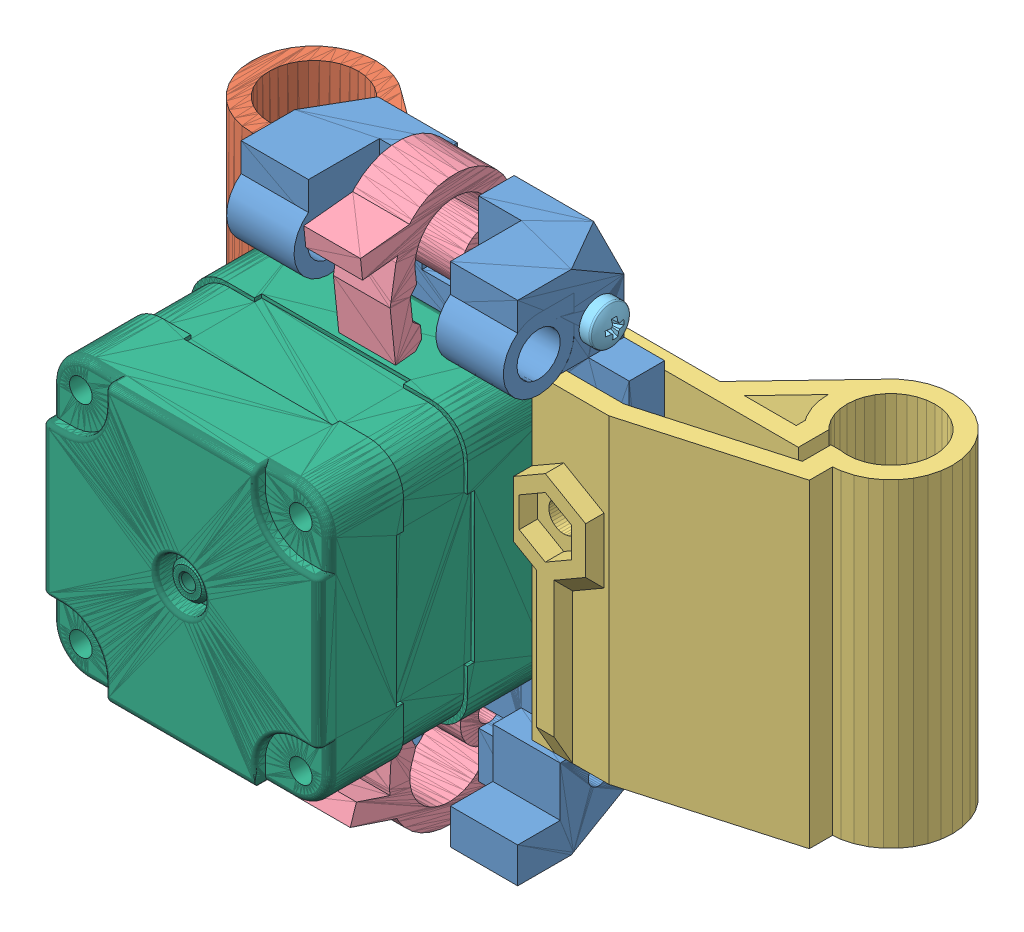
SolidWorks assembly carro y, configuration Valor predeterminado. Lengths in mm.
Overall size (98.79 82.16 55.52).
7 component instances, 6 part files, 10 mates.
Components (placement in the parent):
- carro y block-1: carro y block [Valor predeterminado] at origin size (50.44 71.5 17.04)
- y-bearing-holder-1: y-bearing-holder [Valor predeterminado] at (9.23 58.2501 0) x (-1 0 0) z (0 -1 -0.000001) size (25.76 17.52 45)
- y-bearing-idler solid-1: y-bearing-idler solid [Valor predeterminado] at (31.03 13.2501 12.0203) x (1 0 0) z (0 1 0.000001) size (51.23 29.53 45)
- lock-clip-1: lock-clip [Valor predeterminado] at (29.2204 1.216 23.8542) x (0.000001 0.948821 -0.315816) z (-1 0.000029 0.000083) size (18.28 21.15 8)
- lock-clip-2: lock-clip [Valor predeterminado] at (21.221 74.5161 21.907) x (-0.000037 -0.994667 -0.103142) z (1 -0.000028 -0.000082) size (18.28 21.15 8)
- Pan Head Cross Recess Screw_ISO-2: Pan Head Cross Recess Screw_ISO [ISO 7045 - M3 x 30 - Z --- 30N] at (47.1197 63.5002 3.5499) x (-1 0.000029 0.000082) z (0.000034 0.998146 0.060861) size (32.35 5.6 5.6)
- NEMA17_33 MOTOR-1: NEMA17_33 MOTOR [Valor predeterminado] at (39.6272 16.2496 38.0417) x (0 0.000001 -1) z (-0.000004 1 0.000001) size (49 39 39)
Mates (geometry in assembly coordinates):
- Concêntrico6: concentric aligned: circle of carro y block-1; circle of y-bearing-idler solid-1
- Paralelo1: parallel anti-aligned: plane of carro y block-1 through (15.2185 6.5906 4.0631) normal (1 0 0); plane of y-bearing-idler solid-1 through (31.03 13.2501 -2.5997) normal (-1 0 0)
- Concêntrico7: concentric anti-aligned: circle of carro y block-1; circle of lock-clip-1
- Coincidente8: coincident: line of lock-clip-1 through (21.2185 2.6459 1.0982) axis (0 0.948821 -0.315816); plane of carro y block-1 through (21.2185 6.5906 3.037) normal (1 0 0)
- Concêntrico8: concentric aligned: circle of lock-clip-2; circle of carro y block-1
- Concêntrico12: concentric aligned: circle of carro y block-1; cylinder of Pan Head Cross Recess Screw_ISO-2 through (72.5197 63.4994 3.5479) axis (1 -0.000029 -0.000082) radius 2.8
- Coincidente13: coincident anti-aligned: plane of carro y block-1 through (44.7196 62.7502 2.2511) normal (1 -0.000029 -0.000082); plane of Pan Head Cross Recess Screw_ISO-2 through (44.7198 63.4089 5.0474) normal (-1 0.000029 0.000082)
- Concêntrico15: concentric: circle of carro y block-1; cylinder of NEMA17_33 MOTOR-1 through (35.6294 20.2501 38) axis (0 0.000001 -1) radius 1.6
- Coincidente16: coincident: line of carro y block-1 through (9.26 20.2501 5) axis (1 0 0); plane of NEMA17_33 MOTOR-1 through (22.506 48.6322 5.0001) normal (0 0.000001 -1)
- Paralelo2: parallel: line of carro y block-1 through (5.7185 71.5001 15.0002) axis (1 0.000004 0.000001); plane of NEMA17_33 MOTOR-1 through (30.1265 55.2501 35.5001) normal (-0.000004 1 0.000001)
